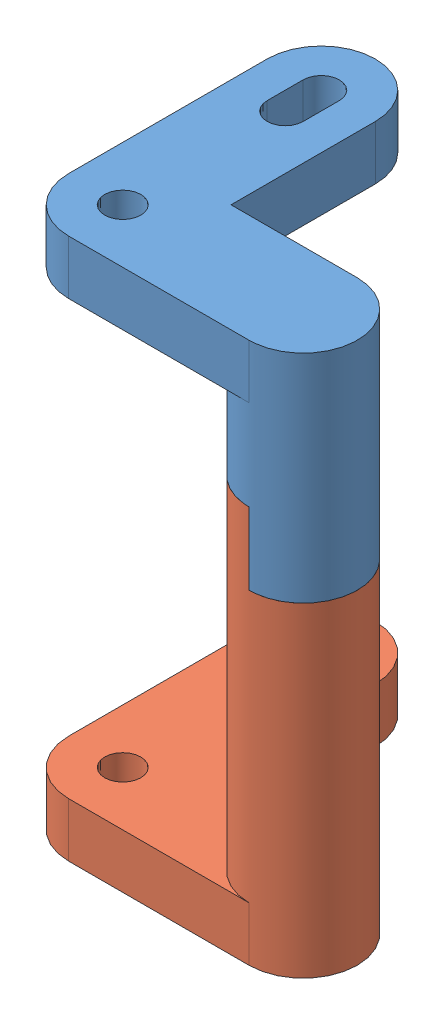
SolidWorks assembly Assem3, configuration Default. Lengths in mm.
Overall size (8 15 8.5).
2 component instances, 2 part files, 3 mates.
Components (placement in the parent):
- clutch_link_1-1: clutch_link_1 [Default] at (-0.5506 -5.4996 6.0173) size (8 6 8.5)
- clutch_link_2-1: clutch_link_2 [Default] at (-0.5506 -5.4996 6.0173) size (8 11 8.5)
Mates (geometry in assembly coordinates):
- Coincident1: coincident: plane of clutch_link_1-1 through (4.4494 5.5004 10.0173) normal (-1 0 0); plane of clutch_link_2-1 through (4.4494 5.5004 13.1649) normal (1 0 0)
- Coincident2: coincident: plane of clutch_link_1-1 through (4.4494 5.5004 8.5173) normal (0 -1 0); plane of clutch_link_2-1 through (4.4494 5.5004 14.6649) normal (0 1 0)
- Coincident3: coincident anti-aligned: circle of clutch_link_1-1; circle of clutch_link_2-1
